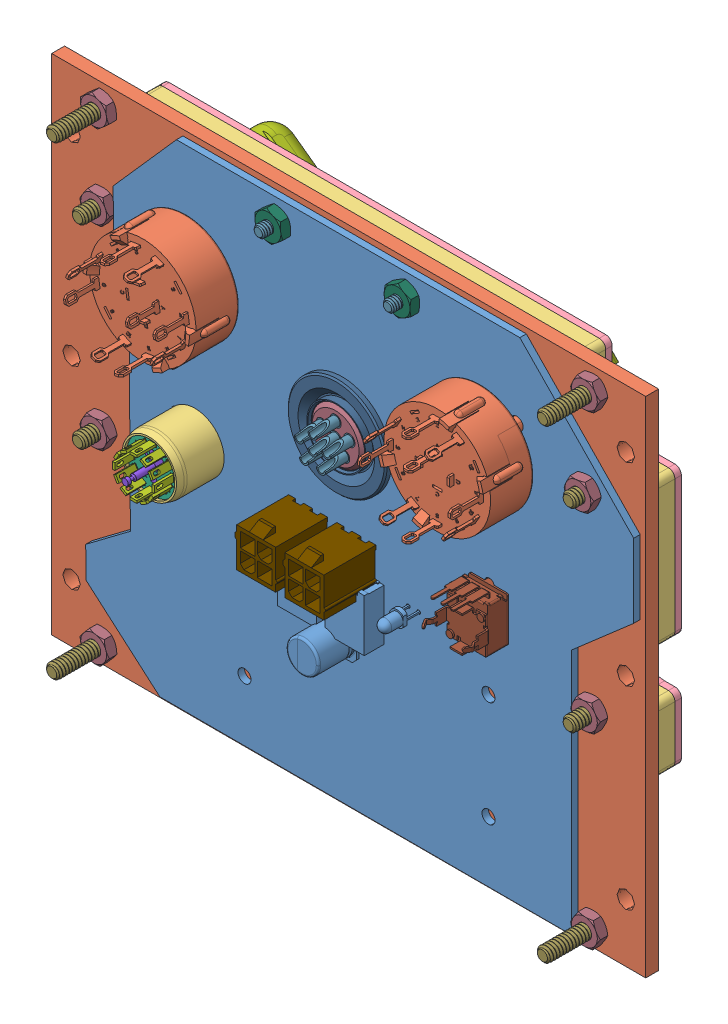
SolidWorks assembly KY58 Panel, configuration Default. Lengths in mm.
Overall size (146.05 123.94 51.19).
107 component instances, 36 part files, 96 mates.
Components (placement in the parent):
- KY58 Panel PCB V2-1: KY58 Panel PCB V2 [Default] at (-68.7194 62.0635 1.6) x (-1 0 0) z (0 0 -1) size (134.72 120.82 16.2)
- KY58 Panel Backplate-1: KY58 Panel Backplate [Default] at origin size (146.05 123.83 3.17)
- KY58 Panel FWD Lightplate-1: KY58 Panel FWD Lightplate [Default] at (0 0 -3.175) x (-1 0 0) z (0 0 -1) size (144.53 82.55 4.76)
- KY58 Panel FWD Legend Plate-1: KY58 Panel FWD Legend Plate [Default] at (0 0 -7.9375) x (-1 0 0) z (0 0 -1) size (144.53 82.55 1.59)
- KY58 Panel AFT Lightplate-1: KY58 Panel AFT Lightplate [Default] at (0 0 -3.175) x (-1 0 0) z (0 0 -1) size (127 36.58 4.76)
- KY58 Panel AFT Legend Plate-1: KY58 Panel AFT Legend Plate [Default] at (0 0 -7.9375) x (-1 0 0) z (0 0 -1) size (127 36.58 1.59)
- MS21384-04DBN v2-1: MS21384-04DBN v2 [Default] at (-109.22 96.901 -9.525) x (-0.587785 -0.809017 0) z (0 0 -1) size (25.4 28.74 19.06)
- MS21387-18BN v4-1: MS21387-18BN v4 [Default] at (-36.83 60.325 -9.525) x (-0.866025 -0.5 0) z (0 0 -1) size (19.05 19.04 16.09)
- MS21384-04DBN v2-2: MS21384-04DBN v2 [Default] at (-36.83 96.901 -9.525) x (0.707107 -0.707107 0) z (0 0 -1) size (25.4 28.74 19.06)
- Korry BP246-A1B1 v3-1: Korry BP246-A1B1 v3 [Default] at (-109.22 60.325 -9.525) x (-0.5 -0.866025 0) z (0 0 -1) size (22.37 22.35 14.44)
- M55116_10-0 v7-1: M55116_10-0 v7 [Default] at (0 0 -3.175) x (-1 0 0) z (0 0 -1) size (34.41 34.41 29.28)
  - Housing Metal-1: Housing Metal [Default] at (73.025 80.137 -6.223) size (24.34 24.34 23.04)
  - O-Ring - Outer-1: O-Ring - Outer [Default] at (73.025 80.137 -6.223) size (22.61 22.61 1.78)
  - Plastic Housing - Upper-1: Plastic Housing - Upper [Default] at (73.025 80.137 -6.223) size (13.16 13.16 16.89)
  - Plastic Housing - Lower-1: Plastic Housing - Lower [Default] at (73.025 80.137 -6.223) size (13.16 13.16 3.81)
  - Solder Cup-1: Solder Cup [Default] at (73.025 80.137 -6.223) size (2.79 2.79 11.66)
  - Retaining Nut-1: Retaining Nut [Default] at (73.025 80.137 -5.7404) x (-0.707107 0.707107 0) z (0 0 1) size (24.33 24.33 3.32)
  - O-Ring - Inner-1: O-Ring - Inner [Default] at (73.025 80.137 -6.223) size (13.46 13.46 2.54)
  - Pogo Spring Asmbly-1: Pogo Spring Asmbly [Default] at origin size (2.95 2.95 19.03)
    - Pogo Spring-1: Pogo Spring [Default] at (73.025 80.137 -6.223) size (2.88 2.88 16.26)
    - Pogo Pin Asmbly-1: Pogo Pin Asmbly [Default] at origin size (2.95 2.95 7.62)
      - Pogo O-Ring-1: Pogo O-Ring [Default] at (73.025 80.137 -6.223) size (2.92 2.92 0.76)
      - Pogo Contact Pin-1: Pogo Contact Pin [Default] at (73.025 80.137 -6.223) size (2.95 2.95 7.62)
  - Solder Cup-2: Solder Cup [Default] at (73.025 83.693 -6.223) size (2.79 2.79 11.66)
  - Pogo Spring Asmbly_2-1: Pogo Spring Asmbly_2 [Default] at (0 12.7 0) size (2.95 2.95 19.03)
    - Pogo Spring-1: Pogo Spring [Default] at (73.025 70.993 -6.223) size (2.88 2.88 16.26)
    - Pogo Pin Asmbly_2-1: Pogo Pin Asmbly_2 [Default] at origin size (2.95 2.95 7.62)
      - Pogo O-Ring-1: Pogo O-Ring [Default] at (73.025 70.993 -6.223) size (2.92 2.92 0.76)
      - Pogo Contact Pin-1: Pogo Contact Pin [Default] at (73.025 70.993 -6.223) size (2.95 2.95 7.62)
  - Pogo Spring Asmbly_3-1: Pogo Spring Asmbly_3 [Default] at (0 19.05 0) size (2.95 2.95 19.03)
    - Pogo Spring-1: Pogo Spring [Default] at (69.643 62.1859 -6.223) size (2.88 2.88 16.26)
    - Pogo Pin Asmbly_3-1: Pogo Pin Asmbly_3 [Default] at origin size (2.95 2.95 7.62)
      - Pogo O-Ring-1: Pogo O-Ring [Default] at (69.643 62.1859 -6.223) size (2.92 2.92 0.76)
      - Pogo Contact Pin-1: Pogo Contact Pin [Default] at (69.643 62.1859 -6.223) size (2.95 2.95 7.62)
  - Solder Cup-3: Solder Cup [Default] at (69.643 81.2359 -6.223) size (2.79 2.79 11.66)
  - Pogo Spring Asmbly_4-1: Pogo Spring Asmbly_4 [Default] at (0 25.4 0) size (2.95 2.95 19.03)
    - Pogo Spring-1: Pogo Spring [Default] at (70.9348 51.8601 -6.223) size (2.88 2.88 16.26)
    - Pogo Pin Asmbly_4-1: Pogo Pin Asmbly_4 [Default] at origin size (2.95 2.95 7.62)
      - Pogo O-Ring-1: Pogo O-Ring [Default] at (70.9348 51.8601 -6.223) size (2.92 2.92 0.76)
      - Pogo Contact Pin-1: Pogo Contact Pin [Default] at (70.9348 51.8601 -6.223) size (2.95 2.95 7.62)
  - Solder Cup-4: Solder Cup [Default] at (70.9348 77.2601 -6.223) size (2.79 2.79 11.66)
  - Pogo Spring Asmbly_5-1: Pogo Spring Asmbly_5 [Default] at (0 31.75 0) size (2.95 2.95 19.03)
    - Pogo Spring-1: Pogo Spring [Default] at (75.1152 45.5101 -6.223) size (2.88 2.88 16.26)
    - Pogo Pin Asmbly_5-1: Pogo Pin Asmbly_5 [Default] at origin size (2.95 2.95 7.62)
      - Pogo O-Ring-1: Pogo O-Ring [Default] at (75.1152 45.5101 -6.223) size (2.92 2.92 0.76)
      - Pogo Contact Pin-1: Pogo Contact Pin [Default] at (75.1152 45.5101 -6.223) size (2.95 2.95 7.62)
  - Solder Cup-5: Solder Cup [Default] at (75.1152 77.2601 -6.223) size (2.79 2.79 11.66)
  - Pogo Spring Asmbly_6-1: Pogo Spring Asmbly_6 [Default] at (0 38.1 0) size (2.95 2.95 19.03)
    - Pogo Spring-1: Pogo Spring [Default] at (76.407 43.1359 -6.223) size (2.88 2.88 16.26)
    - Pogo Pin Asmbly_6-1: Pogo Pin Asmbly_6 [Default] at origin size (2.95 2.95 7.62)
      - Pogo O-Ring-1: Pogo O-Ring [Default] at (76.407 43.1359 -6.223) size (2.92 2.92 0.76)
      - Pogo Contact Pin-1: Pogo Contact Pin [Default] at (76.407 43.1359 -6.223) size (2.95 2.95 7.62)
  - Solder Cup-6: Solder Cup [Default] at (76.4187 81.1885 -6.1973) size (2.79 2.79 11.66)
- A12505RNZQ - SWITCH, ROTARY, 36 DEG, 8 POS, FIXED-1: A12505RNZQ - SWITCH, ROTARY, 36 DEG, 8 POS, FIXED [Default] at (-109.22 96.901 8.839) x (0.809017 -0.587785 0) z (0.587785 0.809017 0) size (26.24 41.71 26.19)
- A12505RNZQ - SWITCH, ROTARY, 36 DEG, 8 POS, FIXED-2: A12505RNZQ - SWITCH, ROTARY, 36 DEG, 8 POS, FIXED [Default] at (-36.83 96.901 8.839) x (0.707107 0.707107 0) z (-0.707107 0.707107 0) size (26.24 41.71 26.19)
- 51M30-01-2-03N-1: 51M30-01-2-03N [Default] at (-109.22 60.325 2.286) x (-0.707107 0.707107 0) z (0 0 1) size (16.37 16.39 34.37)
  - 58R3008-X-1: 58R3008-X [Default] at origin size (14.45 14.33 19.06)
  - 58J2001-1-1: 58J2001-1 [Default] x (0.258819 -0.965926 0) z (0 0 1) size (6.07 7.89 18.87)
  - 58Z3130-1: 58Z3130 [Default] at (0 0 1.3207) x (0.258835 -0.965922 0) z (-0.965922 -0.258835 0) size (13.36 6.25 13.36)
  - 58ZZ3040-5_ASM-1: 58ZZ3040-5_ASM [Default] at (0.0109 -0.0266 7.6015) x (-0.258835 0.965922 0) z (0.965922 0.258835 0) size (13.36 10.5 13.36)
    - 58ZZ3040-X_PLASTIC-1: 58ZZ3040-X_PLASTIC [Default] at origin size (13.36 3.7 13.36)
    - 50C3495-5-B-001-1: 50C3495-5-B-001 [Default] at (-4.2014 0.696 2.4257) x (0.5 0 0.866025) z (0.866025 0 -0.5) size (2 6.75 1.01)
    - 50C3495-5-B-001-2: 50C3495-5-B-001 [Default] at (-2.4257 0.696 4.2014) x (0.866025 0 0.5) z (0.5 0 -0.866025) size (2 6.75 1.01)
    - 50C3495-5-B-001-3: 50C3495-5-B-001 [Default] at (0 0.696 4.8514) x (1 0 0) z (0 0 -1) size (2 6.75 1.01)
    - 50C3495-5-B-001-4: 50C3495-5-B-001 [Default] at (2.4257 0.696 4.2014) x (0.866025 0 -0.5) z (-0.5 0 -0.866025) size (2 6.75 1.01)
    - 50C3495-5-B-001-5: 50C3495-5-B-001 [Default] at (4.2014 0.696 2.4257) x (0.5 0 -0.866025) z (-0.866025 0 -0.5) size (2 6.75 1.01)
    - 50C3495-5-B-001-6: 50C3495-5-B-001 [Default] at (4.8514 0.696 0) x (0 0 -1) z (-1 0 0) size (2 6.75 1.01)
    - 50C3495-5-B-001-7: 50C3495-5-B-001 [Default] at (4.2014 0.696 -2.4257) x (-0.5 0 -0.866025) z (-0.866025 0 0.5) size (2 6.75 1.01)
    - 50C3495-5-B-001-8: 50C3495-5-B-001 [Default] at (2.4257 0.696 -4.2014) x (-0.866025 0 -0.5) z (-0.5 0 0.866025) size (2 6.75 1.01)
    - 50C3495-5-B-001-9: 50C3495-5-B-001 [Default] at (0 0.696 -4.8514) x (-1 0 0) z (0 0 1) size (2 6.75 1.01)
    - 50C3495-5-B-001-10: 50C3495-5-B-001 [Default] at (-2.4257 0.696 -4.2014) x (-0.866025 0 0.5) z (0.5 0 0.866025) size (2 6.75 1.01)
    - 50C3495-5-B-001-11: 50C3495-5-B-001 [Default] at (-4.2014 0.696 -2.4257) x (-0.5 0 0.866025) z (0.866025 0 0.5) size (2 6.75 1.01)
    - 50C3495-5-B-001-12: 50C3495-5-B-001 [Default] at (-4.8514 0.696 0) x (0 0 1) z (1 0 0) size (2 6.75 1.01)
    - 58C3026-10-1: 58C3026-10 [Default] at (0 0.3302 0) size (7.16 8.59 7.16)
  - 06J1025-12-1: 06J1025-12 [Default] at (0 0 -8.382) x (-1 0 0) z (0 0 -1) size (4.75 4.75 0.3)
  - 58J2427-1: 58J2427 [Default] at (0 0 -8.6868) x (-1 0 0) z (0 0 -1) size (4.93 4.93 0.76)
- P0915N-FC20BR10K-1: P0915N-FC20BR10K [Default] at (-36.83 60.325 0) x (1 0 0) z (0 0 -1) size (11.93 12.51 33.35)
- 91249A151 - PHS, 6-32 X .625, 18-8, BLACK-OXIDE-5: 91249A151 - PHS, 6-32 X .625, 18-8, BLACK-OXIDE [91249A151] at (-133.35 98.425 6.35) x (-0.99974 0.022823 0) z (0 0 -1) size (6.86 6.86 18.38)
- 90760A007 - NUT, 6-32, JAM, STEEL, ZINC-PLATED-3: 90760A007 - NUT, 6-32, JAM, STEEL, ZINC-PLATED [90760A007] at (-133.35 98.425 1.1906) x (0.837783 -0.546003 0) z (-0.546003 -0.837783 0) size (6.35 2.99 7.33)
- 91249A151 - PHS, 6-32 X .625, 18-8, BLACK-OXIDE-4: 91249A151 - PHS, 6-32 X .625, 18-8, BLACK-OXIDE [91249A151] at (-133.35 50.673 6.35) x (-0.997514 -0.070465 0) z (0 0 -1) size (6.86 6.86 18.38)
- 90760A007 - NUT, 6-32, JAM, STEEL, ZINC-PLATED-4: 90760A007 - NUT, 6-32, JAM, STEEL, ZINC-PLATED [90760A007] at (-133.35 50.673 1.1906) x (0.88503 -0.465534 0) z (-0.465534 -0.88503 0) size (6.35 2.99 7.33)
- 91249A151 - PHS, 6-32 X .625, 18-8, BLACK-OXIDE-8: 91249A151 - PHS, 6-32 X .625, 18-8, BLACK-OXIDE [91249A151] at (-12.7 50.673 6.35) x (-0.992199 -0.124664 0) z (0 0 -1) size (6.86 6.86 18.38)
- 90760A007 - NUT, 6-32, JAM, STEEL, ZINC-PLATED-5: 90760A007 - NUT, 6-32, JAM, STEEL, ZINC-PLATED [90760A007] at (-12.7 50.673 1.1906) x (0.90906 -0.416664 0) z (-0.416664 -0.90906 0) size (6.35 2.99 7.33)
- 91249A151 - PHS, 6-32 X .625, 18-8, BLACK-OXIDE-9: 91249A151 - PHS, 6-32 X .625, 18-8, BLACK-OXIDE [91249A151] at (-12.7 98.425 6.35) x (-0.990939 -0.13431 0) z (0 0 -1) size (6.86 6.86 18.38)
- 90760A007 - NUT, 6-32, JAM, STEEL, ZINC-PLATED-6: 90760A007 - NUT, 6-32, JAM, STEEL, ZINC-PLATED [90760A007] at (-12.7 98.425 2.7906) x (0.913071 -0.407801 0) z (-0.407801 -0.913071 0) size (6.35 2.99 7.33)
- 91249A151 - PHS, 6-32 X .625, 18-8, BLACK-OXIDE-7: 91249A151 - PHS, 6-32 X .625, 18-8, BLACK-OXIDE [91249A151] at (-12.7 119.0625 12.7) x (-0.995588 -0.09383 0) z (0 0 -1) size (6.86 6.86 18.38)
- 90760A007 - NUT, 6-32, JAM, STEEL, ZINC-PLATED-7: 90760A007 - NUT, 6-32, JAM, STEEL, ZINC-PLATED [90760A007] at (-12.7 119.0625 1.1906) x (0.8957 -0.444659 0) z (-0.444659 -0.8957 0) size (6.35 2.99 7.33)
- 91249A151 - PHS, 6-32 X .625, 18-8, BLACK-OXIDE-11: 91249A151 - PHS, 6-32 X .625, 18-8, BLACK-OXIDE [91249A151] at (-12.7 4.7625 12.7) x (-1 -0.000303 0) z (0 0 -1) size (6.86 6.86 18.38)
- 90760A007 - NUT, 6-32, JAM, STEEL, ZINC-PLATED-8: 90760A007 - NUT, 6-32, JAM, STEEL, ZINC-PLATED [90760A007] at (-12.7 4.7625 1.1906) x (0.850185 -0.526483 0) z (-0.526483 -0.850185 0) size (6.35 2.99 7.33)
- 91249A151 - PHS, 6-32 X .625, 18-8, BLACK-OXIDE-12: 91249A151 - PHS, 6-32 X .625, 18-8, BLACK-OXIDE [91249A151] at (-133.35 4.7625 12.7) x (-0.990161 0.139933 0) z (0 0 -1) size (6.86 6.86 18.38)
- 90760A007 - NUT, 6-32, JAM, STEEL, ZINC-PLATED-9: 90760A007 - NUT, 6-32, JAM, STEEL, ZINC-PLATED [90760A007] at (-133.35 4.7625 1.1906) x (0.767954 -0.640504 0) z (-0.640504 -0.767954 0) size (6.35 2.99 7.33)
- 91249A151 - PHS, 6-32 X .625, 18-8, BLACK-OXIDE-10: 91249A151 - PHS, 6-32 X .625, 18-8, BLACK-OXIDE [91249A151] at (-133.35 119.0625 12.7) x (-0.952417 0.3048 0) z (0 0 -1) size (6.86 6.86 18.38)
- 90760A007 - NUT, 6-32, JAM, STEEL, ZINC-PLATED-10: 90760A007 - NUT, 6-32, JAM, STEEL, ZINC-PLATED [90760A007] at (-133.35 119.0625 1.1906) x (0.649029 -0.760764 0) z (-0.760764 -0.649029 0) size (6.35 2.99 7.33)
- 91249A115 - PHS, 4-40 X .625, 18-8, BLACK-OXIDE-1: 91249A115 - PHS, 4-40 X .625, 18-8, BLACK-OXIDE [91249A115] at (-57.15 117.475 6.35) x (-0.923728 -0.383049 0) z (0 0 -1) size (5.56 5.56 18.18)
- 91841A005 - NUT, 4-40, 18-8-1: 91841A005 - NUT, 4-40, 18-8 [91841A005] at (-57.15 117.475 2.7906) x (1 0 0) z (0 1 0) size (6.35 2.87 7.33)
- 91249A115 - PHS, 4-40 X .625, 18-8, BLACK-OXIDE-2: 91249A115 - PHS, 4-40 X .625, 18-8, BLACK-OXIDE [91249A115] at (-88.9 117.475 6.35) x (-0.85131 -0.524663 0) z (0 0 -1) size (5.56 5.56 18.18)
- 91841A005 - NUT, 4-40, 18-8-2: 91841A005 - NUT, 4-40, 18-8 [91841A005] at (-88.9 117.475 2.7906) x (0.987351 0.158553 0) z (-0.158553 0.987351 0) size (6.35 2.87 7.33)
- 92311A189 - SCREW, SET, 8-32 X .1875, CUP POINT, HEX DRIVE, 18-8-1: 92311A189 - SCREW, SET, 8-32 X .1875, CUP POINT, HEX DRIVE, 18-8 [92311A189] at (-35.3485 65.8541 -14.351) x (0.933013 -0.25 -0.258819) z (0.258819 0.965926 0) size (4.2 4.28 5.07)
- 92311A189 - SCREW, SET, 8-32 X .1875, CUP POINT, HEX DRIVE, 18-8-5: 92311A189 - SCREW, SET, 8-32 X .1875, CUP POINT, HEX DRIVE, 18-8 [92311A189] at (-42.3591 61.8065 -14.351) x (0.25 0.933013 -0.258819) z (-0.965926 0.258819 0) size (4.2 4.28 5.07)
- 92311A189 - SCREW, SET, 8-32 X .1875, CUP POINT, HEX DRIVE, 18-8-7: 92311A189 - SCREW, SET, 8-32 X .1875, CUP POINT, HEX DRIVE, 18-8 [92311A189] at (-42.5513 96.901 -17.399) x (0 0.136843 0.990593) z (-1 0 0) size (4.2 4.28 5.07)
- 92311A189 - SCREW, SET, 8-32 X .1875, CUP POINT, HEX DRIVE, 18-8-8: 92311A189 - SCREW, SET, 8-32 X .1875, CUP POINT, HEX DRIVE, 18-8 [92311A189] at (-36.83 91.1797 -17.399) x (-0.136843 0 0.990593) z (0 -1 0) size (4.2 4.28 5.07)
- 92311A189 - SCREW, SET, 8-32 X .1875, CUP POINT, HEX DRIVE, 18-8-9: 92311A189 - SCREW, SET, 8-32 X .1875, CUP POINT, HEX DRIVE, 18-8 [92311A189] at (-115.2817 96.8411 -17.399) x (-0.449916 -0.810161 0.375787) z (-0.874237 0.4855 0) size (4.2 4.28 5.07)
- 92311A189 - SCREW, SET, 8-32 X .1875, CUP POINT, HEX DRIVE, 18-8-10: 92311A189 - SCREW, SET, 8-32 X .1875, CUP POINT, HEX DRIVE, 18-8 [92311A189] at (-110.1054 102.491 -17.399) x (-0.955723 -0.151372 -0.252349) z (-0.156434 0.987688 0) size (4.2 4.28 5.07)
- 92311A105 - SCREW, SET, 4-40 X .1875, CUP POINT, HEX DRIVE, 18-8-2: 92311A105 - SCREW, SET, 4-40 X .1875, CUP POINT, HEX DRIVE, 18-8 [92311A105] at (-113.3165 59.2273 -17.399) x (0.066987 -0.25 0.965926) z (-0.965926 -0.258819 0) size (3.29 2.93 5.01)
- 92311A105 - SCREW, SET, 4-40 X .1875, CUP POINT, HEX DRIVE, 18-8-3: 92311A105 - SCREW, SET, 4-40 X .1875, CUP POINT, HEX DRIVE, 18-8 [92311A105] at (-109.6896 62.0775 -17.399) x (0.682311 0.182825 0.707833) z (-0.258819 0.965926 0) size (3.29 2.93 5.01)
- Molex_Mini-Fit_Jr_5566-04A_2x02_P4.20mm_Vertical.step-1: Molex_Mini-Fit_Jr_5566-04A_2x02_P4.20mm_Vertical.step [Default] at (-81.383 55.82 1.6) x (1 0 0) z (0 -1 0) size (10.4 16.3 11)
- Molex_Mini-Fit_Jr_5566-04A_2x02_P4.20mm_Vertical.step-2: Molex_Mini-Fit_Jr_5566-04A_2x02_P4.20mm_Vertical.step [Default] at (-69.5298 55.8151 1.6) x (1 0 0) z (0 -1 0) size (10.4 16.3 11)
Mates (geometry in assembly coordinates):
- Concentric1: concentric anti-aligned: cylinder of KY58 Panel FWD Lightplate-1 through (-73.025 80.137 -7.9375) axis (0 0 -1) radius 12.7; cylinder of M55116_10-0 v7-1/Housing Metal-1 through (-73.025 80.137 -16.9787) axis (0 0 1) radius 7.5184
- Parallel2: parallel aligned: line of KY58 Panel Backplate-1 through (123.825 -146.05 123.825) axis (0 0 -1); line of M55116_10-0 v7-1/Housing Metal-1 through (-81.2165 84.8465 0) axis (0 -1 0)
- Coincident2: coincident anti-aligned: plane of KY58 Panel Backplate-1 through (0 0 0) normal (0 0 1); plane of M55116_10-0 v7-1/Housing Metal-1 through (-60.8584 80.137 0) normal (0 0 -1)
- Concentric2: concentric aligned: cylinder of KY58 Panel Backplate-1 through (-109.22 96.901 0) axis (0 0 -1) radius 6.35; cylinder of MS21384-04DBN v2-1 through (-109.22 96.901 -9.525) axis (0 0 -1) radius 4.826
- Angle1: planar angle = 0.628319 rad aligned: plane of MS21384-04DBN v2-1 through (-122.1659 106.3067 -12.573) normal (-0.809017 0.587785 0); plane of KY58 Panel Backplate-1 through (-146.05 123.825 -3.175) normal (-1 0 0)
- Coincident3: coincident anti-aligned: plane of KY58 Panel FWD Legend Plate-1 through (-2.3495 54.483 -9.525) normal (0 0 -1); plane of MS21384-04DBN v2-1 through (-109.22 96.901 -9.525) normal (0 0 1)
- Angle2: planar angle = 0.785398 rad aligned: plane of MS21384-04DBN v2-2 through (-48.1451 85.5859 -12.573) normal (-0.707107 -0.707107 0); plane of KY58 Panel Backplate-1 through (-146.05 123.825 -3.175) normal (-1 0 0)
- Concentric3: concentric aligned: cylinder of KY58 Panel Backplate-1 through (-36.83 96.901 0) axis (0 0 -1) radius 6.35; cylinder of MS21384-04DBN v2-2 through (-36.83 96.901 -9.525) axis (0 0 -1) radius 4.826
- Coincident4: coincident anti-aligned: plane of KY58 Panel FWD Legend Plate-1 through (-2.3495 54.483 -9.525) normal (0 0 -1); plane of MS21384-04DBN v2-2 through (-36.83 96.901 -9.525) normal (0 0 1)
- Concentric4: concentric: cylinder of KY58 Panel Backplate-1 through (-109.22 60.325 0) axis (0 0 -1) radius 3.429; cylinder of Korry BP246-A1B1 v3-1 through (-109.22 60.325 -9.525) axis (0 0 -1) radius 11.176
- Coincident5: coincident: plane of KY58 Panel FWD Legend Plate-1 through (-2.3495 54.483 -9.525) normal (0 0 -1); plane of Korry BP246-A1B1 v3-1 through (-109.22 60.325 -9.525) normal (0 0 1)
- Angle3: planar angle = 0.523599 rad: plane of Korry BP246-A1B1 v3-1 through (-107.6619 60.7885 -12.065) normal (-0.866025 0.5 0); plane of KY58 Panel Backplate-1 through (-146.05 123.825 -3.175) normal (-1 0 0)
- Concentric5: concentric aligned: cone of KY58 Panel Backplate-1 through (-36.83 60.325 0) axis (0 0 -1); cylinder of MS21387-18BN v4-1 through (-36.83 60.325 -9.4378) axis (0 0 -1) radius 34.9066
- Coincident6: coincident anti-aligned: plane of KY58 Panel FWD Legend Plate-1 through (-2.3495 54.483 -9.525) normal (0 0 -1); plane of MS21387-18BN v4-1 through (-45.0789 55.5625 -9.525) normal (0 0 1)
- Angle4: planar angle = 4.18879 rad aligned: plane of MS21387-18BN v4-1 through (-37.4036 57.1635 -9.652) normal (-0.5 0.866025 0); plane of KY58 Panel Backplate-1 through (0 0 -3.175) normal (1 0 0)
- Concentric7: concentric anti-aligned: cylinder of MS21384-04DBN v2-1 through (-109.22 96.901 -13.589) axis (0 0 -1) radius 3.2131; cylinder of A12505RNZQ - SWITCH, ROTARY, 36 DEG, 8 POS, FIXED-1 through (-109.22 96.901 -22.3063) axis (0 0 1) radius 3.1496
- Parallel4: parallel anti-aligned: plane of MS21384-04DBN v2-1 through (-108.4582 93.7795 -13.589) normal (-0.809017 0.587785 0); plane of A12505RNZQ - SWITCH, ROTARY, 36 DEG, 8 POS, FIXED-1 through (-108.5335 93.8271 -20.701) normal (0.809017 -0.587785 0)
- Concentric8: concentric anti-aligned: cylinder of KY58 Panel Backplate-1 through (-36.83 60.325 0) axis (0 0 -1) radius 3.7703; cylinder of EVU-F2MFL3B14 - Pot, 10k Linear, PTH, M9 x 0.75 bushing, No Switch-1 through (-36.83 60.325 -5) axis (0 0 1) radius 4.5
- Parallel5: parallel anti-aligned: plane of MS21387-18BN v4-1 through (-37.4036 57.1635 -9.652) normal (-0.5 0.866025 0); plane of EVU-F2MFL3B14 - Pot, 10k Linear, PTH, M9 x 0.75 bushing, No Switch-1 through (-33.83 60.325 -12.7) normal (0.5 -0.866025 0)
- Coincident9: coincident anti-aligned: plane of KY58 Panel Backplate-1 through (0 0 0) normal (0 0 1); plane of EVU-F2MFL3B14 - Pot, 10k Linear, PTH, M9 x 0.75 bushing, No Switch-1 through (-36.83 60.325 0) normal (0 0 -1)
- Concentric13: concentric aligned: circle of 91249A151 - PHS, 6-32 X .625, 18-8, BLACK-OXIDE-5; unknown of 90760A007 - NUT, 6-32, JAM, STEEL, ZINC-PLATED-3
- Coincident14: coincident anti-aligned: plane of KY58 Panel Backplate-1 through (0 0 0) normal (0 0 1); plane of 90760A007 - NUT, 6-32, JAM, STEEL, ZINC-PLATED-3 through (-135.0091 101.6943 0) normal (0 0 -1)
- Coincident15: coincident anti-aligned: plane of KY58 Panel FWD Legend Plate-1 through (-2.3495 54.483 -9.525) normal (0 0 -1); plane of 91249A151 - PHS, 6-32 X .625, 18-8, BLACK-OXIDE-5 through (-133.35 98.425 -9.525) normal (0 0 1)
- Concentric14: concentric anti-aligned: cylinder of KY58 Panel FWD Legend Plate-1 through (-133.35 98.425 -9.525) axis (0 0 -1) radius 2.1526; cylinder of 91249A151 - PHS, 6-32 X .625, 18-8, BLACK-OXIDE-5 through (-133.35 98.425 6.35) axis (0 0 1) radius 3.429
- Concentric15: concentric aligned: cylinder of 91249A151 - PHS, 6-32 X .625, 18-8, BLACK-OXIDE-4 through (-133.35 50.673 6.35) axis (0 0 1) radius 3.429; unknown of 90760A007 - NUT, 6-32, JAM, STEEL, ZINC-PLATED-4
- Coincident16: coincident anti-aligned: plane of KY58 Panel Backplate-1 through (0 0 0) normal (0 0 1); plane of 90760A007 - NUT, 6-32, JAM, STEEL, ZINC-PLATED-4 through (-135.3066 53.7734 0) normal (0 0 -1)
- Coincident17: coincident anti-aligned: plane of KY58 Panel FWD Legend Plate-1 through (-2.3495 54.483 -9.525) normal (0 0 -1); plane of 91249A151 - PHS, 6-32 X .625, 18-8, BLACK-OXIDE-4 through (-133.35 50.673 -9.525) normal (0 0 1)
- Concentric16: concentric anti-aligned: cylinder of KY58 Panel FWD Legend Plate-1 through (-133.35 50.673 -9.525) axis (0 0 -1) radius 2.1526; cylinder of 91249A151 - PHS, 6-32 X .625, 18-8, BLACK-OXIDE-4 through (-133.35 50.673 6.35) axis (0 0 1) radius 3.429
- Concentric17: concentric aligned: cylinder of 91249A151 - PHS, 6-32 X .625, 18-8, BLACK-OXIDE-8 through (-12.7 50.673 6.35) axis (0 0 1) radius 3.429; unknown of 90760A007 - NUT, 6-32, JAM, STEEL, ZINC-PLATED-5
- Coincident18: coincident anti-aligned: plane of KY58 Panel Backplate-1 through (0 0 0) normal (0 0 1); plane of 90760A007 - NUT, 6-32, JAM, STEEL, ZINC-PLATED-5 through (-14.8225 53.6623 0) normal (0 0 -1)
- Coincident19: coincident anti-aligned: plane of KY58 Panel FWD Legend Plate-1 through (-2.3495 54.483 -9.525) normal (0 0 -1); plane of 91249A151 - PHS, 6-32 X .625, 18-8, BLACK-OXIDE-8 through (-12.7 50.673 -9.525) normal (0 0 1)
- Concentric18: concentric anti-aligned: cylinder of KY58 Panel FWD Legend Plate-1 through (-12.7 50.673 -9.525) axis (0 0 -1) radius 2.1526; cylinder of 91249A151 - PHS, 6-32 X .625, 18-8, BLACK-OXIDE-8 through (-12.7 50.673 6.35) axis (0 0 1) radius 3.429
- Concentric19: concentric aligned: cylinder of 91249A151 - PHS, 6-32 X .625, 18-8, BLACK-OXIDE-9 through (-12.7 98.425 6.35) axis (0 0 1) radius 3.429; unknown of 90760A007 - NUT, 6-32, JAM, STEEL, ZINC-PLATED-6
- Coincident20: coincident anti-aligned: plane of KY58 Panel PCB V2-1 through (-70.0219 60.5481 1.6) normal (0 0 1); plane of 90760A007 - NUT, 6-32, JAM, STEEL, ZINC-PLATED-6 through (-14.8515 101.3935 1.6) normal (0 0 -1)
- Coincident21: coincident anti-aligned: plane of KY58 Panel FWD Legend Plate-1 through (-2.3495 54.483 -9.525) normal (0 0 -1); plane of 91249A151 - PHS, 6-32 X .625, 18-8, BLACK-OXIDE-9 through (-12.7 98.425 -9.525) normal (0 0 1)
- Concentric20: concentric anti-aligned: cylinder of KY58 Panel FWD Legend Plate-1 through (-12.7 98.425 -9.525) axis (0 0 -1) radius 2.1526; cylinder of 91249A151 - PHS, 6-32 X .625, 18-8, BLACK-OXIDE-9 through (-12.7 98.425 6.35) axis (0 0 1) radius 3.429
- Concentric21: concentric aligned: cylinder of 91249A151 - PHS, 6-32 X .625, 18-8, BLACK-OXIDE-7 through (-12.7 119.0625 12.7) axis (0 0 1) radius 3.429; unknown of 90760A007 - NUT, 6-32, JAM, STEEL, ZINC-PLATED-7
- Concentric22: concentric anti-aligned: cylinder of KY58 Panel Backplate-1 through (-12.7 119.0625 -3.175) axis (0 0 -1) radius 2.1526; cylinder of 91249A151 - PHS, 6-32 X .625, 18-8, BLACK-OXIDE-7 through (-12.7 119.0625 12.7) axis (0 0 1) radius 3.429
- Coincident27: coincident anti-aligned: plane of KY58 Panel Backplate-1 through (0 0 0) normal (0 0 1); plane of 90760A007 - NUT, 6-32, JAM, STEEL, ZINC-PLATED-7 through (-14.7287 122.1162 0) normal (0 0 -1)
- Coincident28: coincident anti-aligned: plane of KY58 Panel Backplate-1 through (0 0 -3.175) normal (0 0 -1); plane of 91249A151 - PHS, 6-32 X .625, 18-8, BLACK-OXIDE-7 through (-12.7 119.0625 -3.175) normal (0 0 1)
- Concentric23: concentric aligned: cylinder of 91249A151 - PHS, 6-32 X .625, 18-8, BLACK-OXIDE-11 through (-12.7 4.7625 12.7) axis (0 0 1) radius 3.429; unknown of 90760A007 - NUT, 6-32, JAM, STEEL, ZINC-PLATED-8
- Coincident29: coincident anti-aligned: plane of KY58 Panel Backplate-1 through (0 0 0) normal (0 0 1); plane of 90760A007 - NUT, 6-32, JAM, STEEL, ZINC-PLATED-8 through (-14.4342 7.9925 0) normal (0 0 -1)
- Concentric24: concentric anti-aligned: cylinder of KY58 Panel Backplate-1 through (-12.7 4.7625 -3.175) axis (0 0 -1) radius 2.1526; cylinder of 91249A151 - PHS, 6-32 X .625, 18-8, BLACK-OXIDE-11 through (-12.7 4.7625 12.7) axis (0 0 1) radius 3.429
- Coincident31: coincident anti-aligned: plane of KY58 Panel Backplate-1 through (0 0 -3.175) normal (0 0 -1); plane of 91249A151 - PHS, 6-32 X .625, 18-8, BLACK-OXIDE-11 through (-12.7 4.7625 -3.175) normal (0 0 1)
- Concentric25: concentric aligned: cylinder of 91249A151 - PHS, 6-32 X .625, 18-8, BLACK-OXIDE-12 through (-133.35 4.7625 12.7) axis (0 0 1) radius 3.429; unknown of 90760A007 - NUT, 6-32, JAM, STEEL, ZINC-PLATED-9
- Coincident32: coincident anti-aligned: plane of KY58 Panel Backplate-1 through (0 0 0) normal (0 0 1); plane of 90760A007 - NUT, 6-32, JAM, STEEL, ZINC-PLATED-9 through (-134.6142 8.2038 0) normal (0 0 -1)
- Concentric26: concentric anti-aligned: cylinder of KY58 Panel Backplate-1 through (-133.35 4.7625 -3.175) axis (0 0 -1) radius 2.1526; cylinder of 91249A151 - PHS, 6-32 X .625, 18-8, BLACK-OXIDE-12 through (-133.35 4.7625 12.7) axis (0 0 1) radius 3.429
- Coincident33: coincident anti-aligned: plane of KY58 Panel Backplate-1 through (0 0 -3.175) normal (0 0 -1); plane of 91249A151 - PHS, 6-32 X .625, 18-8, BLACK-OXIDE-12 through (-133.35 4.7625 -3.175) normal (0 0 1)
- Concentric27: concentric aligned: cylinder of 91249A151 - PHS, 6-32 X .625, 18-8, BLACK-OXIDE-10 through (-133.35 119.0625 12.7) axis (0 0 1) radius 3.429; unknown of 90760A007 - NUT, 6-32, JAM, STEEL, ZINC-PLATED-10
- Coincident34: coincident anti-aligned: plane of KY58 Panel Backplate-1 through (0 0 0) normal (0 0 1); plane of 90760A007 - NUT, 6-32, JAM, STEEL, ZINC-PLATED-10 through (-134.0161 122.6677 0) normal (0 0 -1)
- Concentric28: concentric anti-aligned: cylinder of KY58 Panel Backplate-1 through (-133.35 119.0625 -3.175) axis (0 0 -1) radius 2.1526; cylinder of 91249A151 - PHS, 6-32 X .625, 18-8, BLACK-OXIDE-10 through (-133.35 119.0625 12.7) axis (0 0 1) radius 3.429
- Coincident35: coincident anti-aligned: plane of KY58 Panel Backplate-1 through (0 0 -3.175) normal (0 0 -1); plane of 91249A151 - PHS, 6-32 X .625, 18-8, BLACK-OXIDE-10 through (-133.35 119.0625 -3.175) normal (0 0 1)
- Concentric29: concentric: cylinder of Korry BP246-A1B1 v3-1 through (-109.22 60.325 -16.8275) axis (0 0 1) radius 1.6256; cylinder of 51M30-01-2-03N-1/58J2001-1-1 through (-109.22 60.325 2.286) axis (0 0 -1) radius 1.5875
- Parallel6: parallel: plane of Korry BP246-A1B1 v3-1 through (-108.8424 58.7439 -12.065) normal (-0.866025 0.5 0); plane of 51M30-01-2-03N-1/58J2001-1-1 through (-109.2419 58.7377 -15.5702) normal (0.866025 -0.5 0)
- Coincident36: coincident anti-aligned: plane of KY58 Panel Backplate-1 through (0 0 0) normal (0 0 1); plane of 51M30-01-2-03N-1/58R3008-X-1 through (-109.22 60.325 0) normal (0 0 -1)
- Concentric30: concentric anti-aligned: cylinder of 91249A115 - PHS, 4-40 X .625, 18-8, BLACK-OXIDE-1 through (-57.15 117.475 6.35) axis (0 0 1) radius 2.7813; unknown of 91841A005 - NUT, 4-40, 18-8-1
- Coincident37: coincident anti-aligned: plane of KY58 Panel PCB V2-1 through (-70.0219 60.5481 1.6) normal (0 0 1); plane of 91841A005 - NUT, 4-40, 18-8-1 through (-60.325 115.6419 1.6) normal (0 0 -1)
- Coincident38: coincident anti-aligned: plane of KY58 Panel FWD Legend Plate-1 through (-2.3495 54.483 -9.525) normal (0 0 -1); plane of 91249A115 - PHS, 4-40 X .625, 18-8, BLACK-OXIDE-1 through (-57.15 117.475 -9.525) normal (0 0 1)
- Concentric31: concentric anti-aligned: cylinder of KY58 Panel FWD Legend Plate-1 through (-57.15 117.475 -9.525) axis (0 0 -1) radius 1.7272; cylinder of 91249A115 - PHS, 4-40 X .625, 18-8, BLACK-OXIDE-1 through (-57.15 117.475 6.35) axis (0 0 1) radius 2.7813
- Concentric32: concentric anti-aligned: cylinder of 91249A115 - PHS, 4-40 X .625, 18-8, BLACK-OXIDE-2 through (-88.9 117.475 6.35) axis (0 0 1) radius 2.7813; unknown of 91841A005 - NUT, 4-40, 18-8-2
- Coincident39: coincident anti-aligned: plane of KY58 Panel PCB V2-1 through (-70.0219 60.5481 1.6) normal (0 0 1); plane of 91841A005 - NUT, 4-40, 18-8-2 through (-91.7442 115.1617 1.6) normal (0 0 -1)
- Coincident40: coincident anti-aligned: plane of KY58 Panel FWD Legend Plate-1 through (-2.3495 54.483 -9.525) normal (0 0 -1); plane of 91249A115 - PHS, 4-40 X .625, 18-8, BLACK-OXIDE-2 through (-88.9 117.475 -9.525) normal (0 0 1)
- Concentric33: concentric anti-aligned: cylinder of KY58 Panel FWD Legend Plate-1 through (-88.9 117.475 -9.525) axis (0 0 -1) radius 1.7272; cylinder of 91249A115 - PHS, 4-40 X .625, 18-8, BLACK-OXIDE-2 through (-88.9 117.475 6.35) axis (0 0 1) radius 2.7813
- Concentric34: concentric aligned: cylinder of KY58 Panel Backplate-1 through (-36.83 60.325 0) axis (0 0 -1) radius 3.7703; cylinder of P0915N-FC20BR10K-1 through (-36.83 60.325 -5) axis (0 0 -1) radius 3
- Coincident41: coincident anti-aligned: plane of KY58 Panel Backplate-1 through (0 0 0) normal (0 0 1); plane of P0915N-FC20BR10K-1 through (-36.83 60.325 0) normal (0 0 -1)
- Parallel7: parallel anti-aligned: plane of MS21387-18BN v4-1 through (-33.6188 60.2147 -25.529) normal (-0.5 0.866025 0); plane of P0915N-FC20BR10K-1 through (-24.865 65.501 -8) normal (0.5 -0.866025 0)
- Concentric35: concentric: cylinder of KY58 Panel Backplate-1 through (-36.83 60.325 0) axis (0 0 -1) radius 3.7703; cylinder of 51M30-01-2-03N-1/P0915N-FC20BR10K-1 through (-36.83 60.325 -5) axis (0 0 -1) radius 3
- Coincident43: coincident: plane of KY58 Panel Backplate-1 through (0 0 0) normal (0 0 1); plane of 51M30-01-2-03N-1/P0915N-FC20BR10K-1 through (-36.83 60.325 0) normal (0 0 -1)
- Parallel8: parallel: plane of MS21387-18BN v4-1 through (-33.6188 60.2147 -25.529) normal (-0.5 0.866025 0); plane of 51M30-01-2-03N-1/P0915N-FC20BR10K-1 through (-24.865 65.501 -8) normal (0.5 -0.866025 0)
- Concentric36: concentric aligned: cylinder of MS21387-18BN v4-1 through (-36.83 60.325 -14.351) axis (0.258819 0.965926 0) radius 1.7082; cylinder of 92311A189 - SCREW, SET, 8-32 X .1875, CUP POINT, HEX DRIVE, 18-8-1 through (-35.8761 63.8852 -14.351) axis (0.258819 0.965926 0) radius 1029.7443
- Tangent1: tangent: cylinder of P0915N-FC20BR10K-1 through (-36.83 60.325 -5) axis (0 0 -1) radius 3; circle of 92311A189 - SCREW, SET, 8-32 X .1875, CUP POINT, HEX DRIVE, 18-8-1
- Concentric40: concentric aligned: cylinder of MS21387-18BN v4-1 through (-36.83 60.325 -14.351) axis (-0.965926 0.258819 0) radius 1.7082; cylinder of 92311A189 - SCREW, SET, 8-32 X .1875, CUP POINT, HEX DRIVE, 18-8-5 through (-40.3902 61.2789 -14.351) axis (-0.965926 0.258819 0) radius 1029.7443
- Tangent4: tangent: cylinder of P0915N-FC20BR10K-1 through (-36.83 60.325 -5) axis (0 0 -1) radius 3; circle of 92311A189 - SCREW, SET, 8-32 X .1875, CUP POINT, HEX DRIVE, 18-8-5
- Concentric43: concentric aligned: cylinder of MS21384-04DBN v2-2 through (-36.83 96.901 -17.399) axis (-1 0 0) radius 1.7082; cylinder of 92311A189 - SCREW, SET, 8-32 X .1875, CUP POINT, HEX DRIVE, 18-8-7 through (-40.513 96.901 -17.399) axis (-1 0 0) radius 1029.7443
- Tangent9: tangent: cylinder of A12505RNZQ - SWITCH, ROTARY, 36 DEG, 8 POS, FIXED-1 through (-109.22 96.901 -20.7063) axis (0 0 1) radius 3.1496; unknown of 92311A189 - SCREW, SET, 8-32 X .1875, CUP POINT, HEX DRIVE, 18-8-9
- Concentric46: concentric anti-aligned: cylinder of MS21384-04DBN v2-1 through (-109.22 96.901 -17.399) axis (-0.156434 0.987688 0) radius 1.7082; cylinder of 92311A189 - SCREW, SET, 8-32 X .1875, CUP POINT, HEX DRIVE, 18-8-10 through (-109.6792 99.8004 -17.399) axis (0.156434 -0.987688 0) radius 785.3982
- Concentric47: concentric aligned: cylinder of Korry BP246-A1B1 v3-1 through (-110.3438 60.0239 -17.399) axis (-0.965926 -0.258819 0) radius 1.1354; cylinder of 92311A105 - SCREW, SET, 4-40 X .1875, CUP POINT, HEX DRIVE, 18-8-2 through (-111.2426 59.7831 -17.399) axis (-0.965926 -0.258819 0) radius 1029.7443
- Tangent11: tangent: unknown of 92311A105 - SCREW, SET, 4-40 X .1875, CUP POINT, HEX DRIVE, 18-8-2; cylinder of Korry BP246-A1B1 v3-1 through (-109.22 60.325 -12.065) axis (0 0 -1) radius 1.6256
- Concentric48: concentric aligned: cylinder of Korry BP246-A1B1 v3-1 through (-109.5211 61.4488 -17.399) axis (-0.258819 0.965926 0) radius 1.1354; cylinder of 92311A105 - SCREW, SET, 4-40 X .1875, CUP POINT, HEX DRIVE, 18-8-3 through (-109.1339 60.0036 -17.399) axis (-0.258819 0.965926 0) radius 1029.7443
- Tangent12: tangent: plane of Korry BP246-A1B1 v3-1 through (-107.6619 60.7885 -12.065) normal (-0.866025 0.5 0); circle of 92311A105 - SCREW, SET, 4-40 X .1875, CUP POINT, HEX DRIVE, 18-8-3
- Coincident44: coincident anti-aligned: plane of KY58 Panel PCB V2-1 through (-70.0219 60.5481 1.6) normal (0 0 1); plane of A12505RNZQ - SWITCH, ROTARY, 36 DEG, 8 POS, FIXED-2 through (-36.83 96.901 1.6) normal (0 0 -1)
- Concentric50: concentric anti-aligned: unknown of KY58 Panel Backplate-1; unknown of A12505RNZQ - SWITCH, ROTARY, 36 DEG, 8 POS, FIXED-2
- Coincident45: coincident anti-aligned: unknown of KY58 Panel PCB V2-1; unknown of KY58 Panel Backplate-1
- Coincident46: coincident anti-aligned: plane of KY58 Panel Backplate-1 through (0 0 -3.175) normal (0 0 -1); plane of KY58 Panel FWD Lightplate-1 through (-2.3495 54.483 -3.175) normal (0 0 1)
- Coincident47: coincident anti-aligned: plane of KY58 Panel PCB V2-1 through (-70.0219 60.5481 1.6) normal (0 0 1); plane of A12505RNZQ - SWITCH, ROTARY, 36 DEG, 8 POS, FIXED-1 through (-109.22 96.901 1.6) normal (0 0 -1)
- Concentric55: concentric aligned: cylinder of KY58 Panel Backplate-1 through (-12.7 98.425 -3.175) axis (0 0 -1) radius 2.1526; cylinder of KY58 Panel FWD Lightplate-1 through (-12.7 98.425 -7.9375) axis (0 0 -1) radius 2.1526
- Concentric56: concentric anti-aligned: cylinder of KY58 Panel PCB V2-1 through (-12.7 98.425 1.6) axis (0 0 1) radius 2.1526; cylinder of KY58 Panel Backplate-1 through (-12.7 98.425 -3.175) axis (0 0 -1) radius 2.1526
- Concentric57: concentric aligned: cylinder of KY58 Panel FWD Lightplate-1 through (-12.7 98.425 -7.9375) axis (0 0 -1) radius 2.1526; cylinder of KY58 Panel FWD Legend Plate-1 through (-12.7 98.425 -9.525) axis (0 0 -1) radius 2.1526
- Coincident49: coincident aligned: circle of KY58 Panel FWD Lightplate-1; circle of KY58 Panel FWD Legend Plate-1
- Distance1: distance = 9.525 mm: line of KY58 Panel AFT Lightplate-1 through (-9.525 38.862 -3.175) axis (0 -1 0); line of KY58 Panel Backplate-1 through (0 0 -3.175) axis (0 1 0)
- Distance2: distance = 2.286 mm: line of KY58 Panel AFT Lightplate-1 through (-22.225 2.286 -3.175) axis (-1 0 0); line of KY58 Panel Backplate-1 through (-146.05 0 -3.175) axis (1 0 0)
- Coincident55: coincident anti-aligned: plane of KY58 Panel Backplate-1 through (0 0 -3.175) normal (0 0 -1); plane of KY58 Panel AFT Lightplate-1 through (0 0 -3.175) normal (0 0 1)
- Parallel11: parallel aligned: line of MS21384-04DBN v2-2 through (-33.6278 97.1652 -25.273) axis (-0.707107 0.707107 0); line of A12505RNZQ - SWITCH, ROTARY, 36 DEG, 8 POS, FIXED-2 through (-33.7976 97.2093 -19.101) axis (-0.707107 0.707107 0)
- Concentric58: concentric anti-aligned: circle of KY58 Panel Backplate-1; circle of A12505RNZQ - SWITCH, ROTARY, 36 DEG, 8 POS, FIXED-1
- Coincident57: coincident anti-aligned: plane of KY58 Panel PCB V2-1 through (-70.0219 60.5481 1.6) normal (0 0 1); plane of Molex_Mini-Fit_Jr_5566-04A_2x02_P4.20mm_Vertical.step-2 through (-74.3298 51.0151 1.6) normal (0 0 -1)
- Coincident58: coincident anti-aligned: plane of KY58 Panel PCB V2-1 through (-70.0219 60.5481 1.6) normal (0 0 1); plane of Molex_Mini-Fit_Jr_5566-04A_2x02_P4.20mm_Vertical.step-1 through (-86.183 51.02 1.6) normal (0 0 -1)
